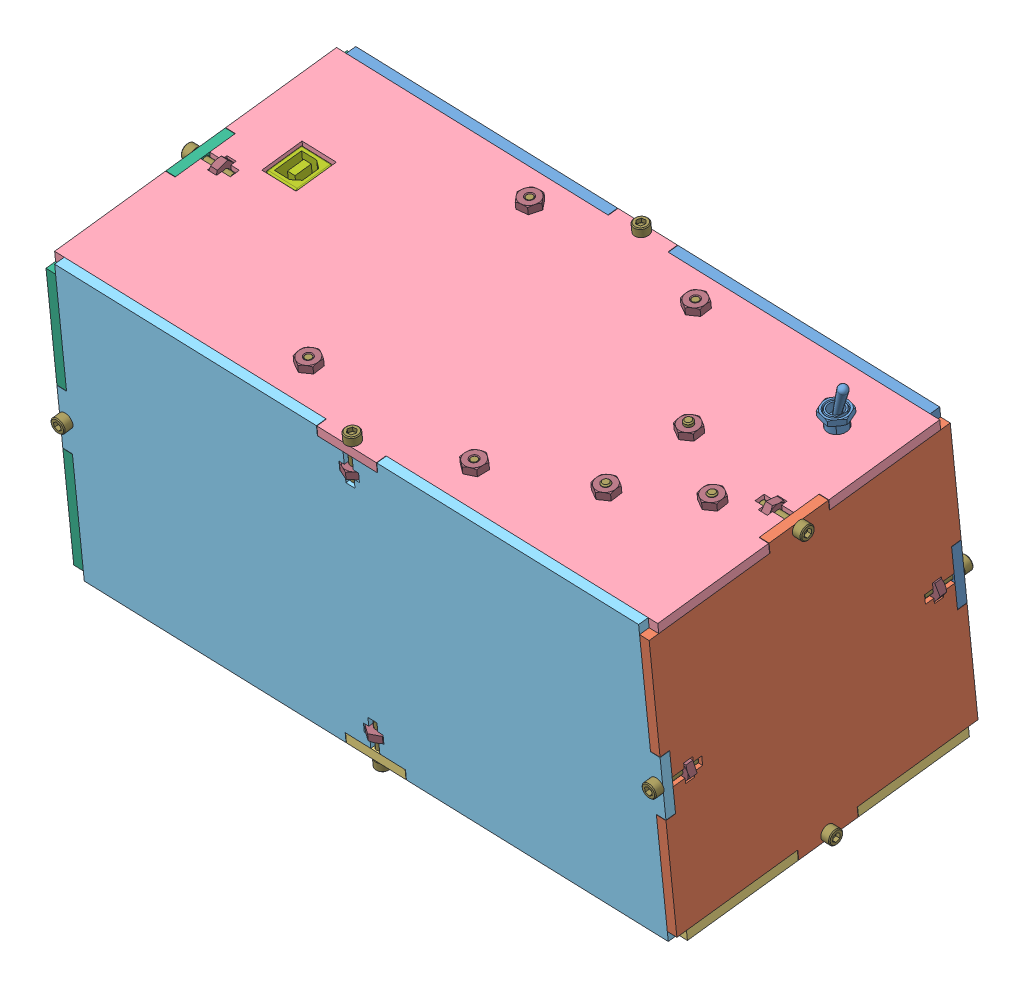
SolidWorks assembly BoxAssembly, configuration Default. Lengths in mm.
Overall size (208.93 126.48 114.42).
72 component instances, 20 part files, 161 mates.
Components (placement in the parent):
- FrontWall-3: FrontWall [Default] at (-132.6402 325.3344 298.0209) x (0.999441 -0.033422 0.001061) z (-0.005434 -0.131017 0.991365) size (200 100 3.18)
- TopWall-2: TopWall [Default] at (-32.9678 315.4413 347.6953) x (0.032994 0.990817 0.131126) z (-0.999441 0.033422 -0.001061) size (100 100 3.18)
- RightWall-1: RightWall [Default] at (-134.5616 269.2427 341.0329) x (0.005434 0.131017 -0.991365) z (0.032994 0.990817 0.131126) size (100 200 3.18)
- LeftWall-5: LeftWall [Default] at (-131.3671 365.1735 353.7285) x (-0.005434 -0.131017 0.991365) z (0.032994 0.990817 0.131126) size (100 200 3.18)
- BackWall-1: BackWall [Default] at (-133.1663 312.6493 394.0049) x (0.999441 -0.033422 0.001061) z (-0.005434 -0.131017 0.991365) size (200 100 3.18)
- BottomWall-1: BottomWall [Default] at (-232.856 322.1257 347.4831) x (-0.032994 -0.990817 -0.131126) z (0.999441 -0.033422 0.001061) size (100 100 3.18)
- ArduinoUno (2)-1: ArduinoUno (2) [Default] at (-216.6407 331.9316 348.8679) x (-0.032994 -0.990817 -0.131126) z (-0.005434 -0.131017 0.991365) size (74.8 12.1 53.3)
- 25x.5 Aluminum Hex Female Female Standoff-1: 25x.5 Aluminum Hex Female Female Standoff [Default] at (-222.2818 352.5481 327.2013) x (0.00659 0.165736 -0.986148) z (0.999441 -0.033422 0.001061) size (6.35 8.06 12.7)
- 25x.5 Aluminum Hex Female Female Standoff-2: 25x.5 Aluminum Hex Female Female Standoff [Default] at (-222.4914 347.8052 375.294) x (-0.020236 -0.579254 0.814896) z (0.999441 -0.033422 0.001061) size (6.35 8.06 12.7)
- 25x.5 Aluminum Hex Female Female Standoff-3: 25x.5 Aluminum Hex Female Female Standoff [Default] at (-224.041 300.21 335.708) x (0.001061 -0.000018 -0.999999) z (0.999441 -0.033422 0.001061) size (6.35 8.06 12.7)
- 25x.5 Aluminum Hex Female Female Standoff-4: 25x.5 Aluminum Hex Female Female Standoff [Default] at (-224.1926 296.5547 363.367) x (-0.023209 -0.670488 0.741557) z (-0.999441 0.033422 -0.001061) size (6.35 8.06 12.7)
- breadboardbracket-1: breadboardbracket [Default] at (-130.399 365.2511 352.8986) x (-0.999441 0.033422 -0.001061) z (-0.032994 -0.990817 -0.131126) size (93 81 12)
- ledmatrix-1: ledmatrix [Default] at (-75.3439 276.7943 322.4548) x (-0.999441 0.033422 -0.001061) z (-0.032994 -0.990817 -0.131126) size (26 20 7)
- ledmatrix-2: ledmatrix [Default] at (-75.5838 271.5752 361.9513) x (-0.999441 0.033422 -0.001061) z (-0.032994 -0.990817 -0.131126) size (26 20 7)
- Ultrasonic holder-1: Ultrasonic holder [Default] at (-120.0997 285.6163 366.5083) x (0.141058 -0.981567 -0.128949) z (0.989986 0.139139 0.023815) size (23.16 47 32.54)
- socket head cap screw_ai-1: socket head cap screw_ai [HX-SHCS 0.112-40x0.5x0.5-N] at (-237.2829 274.6616 341.186) x (0.999441 -0.033422 0.001061) z (0.013936 0.445184 0.895331) size (15.54 4.65 4.65)
- socket head cap screw_ai-2: socket head cap screw_ai [HX-SHCS 0.112-40x0.5x0.5-N] at (-230.5699 328.9824 295.0967) x (-0.005434 -0.131017 0.991365) z (-0.991365 0.130596 0.011825) size (15.54 4.65 4.65)
- socket head cap screw_ai-3: socket head cap screw_ai [HX-SHCS 0.112-40x0.5x0.5-N] at (-134.3946 272.7128 293.0744) x (0.032994 0.990817 0.131126) z (0.177502 -0.134921 0.974828) size (15.54 4.65 4.65)
- socket head cap screw_ai-4: socket head cap screw_ai [HX-SHCS 0.112-40x0.5x0.5-N] at (-134.9163 260.1352 388.2454) x (0.032994 0.990817 0.131126) z (0.089842 0.127726 -0.987732) size (15.54 4.65 4.65)
- socket head cap screw_ai-5: socket head cap screw_ai [HX-SHCS 0.112-40x0.5x0.5-N] at (-31.7083 267.7871 341.4043) x (-0.999441 0.033422 -0.001061) z (0.001061 0.063432 0.997986) size (15.54 4.65 4.65)
- socket head cap screw_ai-6: socket head cap screw_ai [HX-SHCS 0.112-40x0.5x0.5-N] at (-35.2539 308.5846 400.0817) x (0.005434 0.131017 -0.991365) z (0.9972 0.073227 0.015144) size (15.54 4.65 4.65)
- socket head cap screw_ai-7: socket head cap screw_ai [HX-SHCS 0.112-40x0.5x0.5-N] at (-231.1443 315.1352 399.8737) x (0.005434 0.131017 -0.991365) z (0.991365 0.129184 0.022507) size (15.54 4.65 4.65)
- socket head cap screw_ai-8: socket head cap screw_ai [HX-SHCS 0.112-40x0.5x0.5-N] at (-234.1155 369.7799 353.7741) x (0.999441 -0.033422 0.001061) z (-0.001061 0.000018 0.999999) size (15.54 4.65 4.65)
- socket head cap screw_ai-9: socket head cap screw_ai [HX-SHCS 0.112-40x0.5x0.5-N] at (-28.5409 362.9054 353.9924) x (-0.999441 0.033422 -0.001061) z (0.001061 0.063432 0.997986) size (15.54 4.65 4.65)
- socket head cap screw_ai-10: socket head cap screw_ai [HX-SHCS 0.112-40x0.5x0.5-N] at (-34.6795 322.4318 295.3047) x (-0.005434 -0.131017 0.991365) z (-0.991365 0.130596 0.011825) size (15.54 4.65 4.65)
- socket head cap screw_ai-11: socket head cap screw_ai [HX-SHCS 0.112-40x0.5x0.5-N] at (-130.9075 377.4318 306.933) x (-0.032994 -0.990817 -0.131126) z (0.175575 -0.134903 0.975179) size (15.54 4.65 4.65)
- socket head cap screw_ai-12: socket head cap screw_ai [HX-SHCS 0.112-40x0.5x0.5-N] at (-131.4292 364.8542 402.104) x (-0.032994 -0.990817 -0.131126) z (0.131126 -0.134355 0.982219) size (15.54 4.65 4.65)
- machine screw nut hex_ai-1: machine screw nut hex_ai [MSHXNUT 0.112-40-S-N] at (-227.0085 274.318 341.1969) x (0.027312 0.834212 0.550767) z (-0.999441 0.033422 -0.001061) size (6.35 7.33 2.49)
- machine screw nut hex_ai-2: machine screw nut hex_ai [MSHXNUT 0.112-40-S-N] at (-230.6244 327.669 305.0349) x (0.849044 -0.524352 -0.064644) z (0.005434 0.131017 -0.991365) size (6.35 7.33 2.49)
- socket button head cap screw_ai-1: socket button head cap screw_ai [SBHCSCREW 0.112-40x0.375-HX-N] at (-235.2151 296.9232 363.3553) x (0.999441 -0.033422 0.001061) z (-0.001061 0.000018 0.999999) size (11.02 5.41 5.41)
- socket button head cap screw_ai-2: socket button head cap screw_ai [SBHCSCREW 0.112-40x0.375-HX-N] at (-233.3042 352.9167 327.1896) x (0.999441 -0.033422 0.001061) z (0.012253 0.336514 -0.941599) size (11.02 5.41 5.41)
- socket button head cap screw_ai-3: socket button head cap screw_ai [SBHCSCREW 0.112-40x0.375-HX-N] at (-235.0634 300.5786 335.6962) x (0.999441 -0.033422 0.001061) z (-0.001061 0.000018 0.999999) size (11.02 5.41 5.41)
- socket button head cap screw_ai-4: socket button head cap screw_ai [SBHCSCREW 0.112-40x0.375-HX-N] at (-233.5139 348.1738 375.2823) x (0.999441 -0.033422 0.001061) z (-0.001061 0.000018 0.999999) size (11.02 5.41 5.41)
- machine screw nut hex_ai-3: machine screw nut hex_ai [MSHXNUT 0.112-40-S-N] at (-224.0963 369.4449 353.7847) x (0.025816 0.751053 -0.659737) z (-0.999441 0.033422 -0.001061) size (6.35 7.33 2.49)
- machine screw nut hex_ai-5: machine screw nut hex_ai [MSHXNUT 0.112-40-S-N] at (-131.2383 367.4991 305.6185) x (0.9951 -0.044802 0.088146) z (0.032994 0.990817 0.131126) size (6.35 7.33 2.49)
- machine screw nut hex_ai-10: machine screw nut hex_ai [MSHXNUT 0.112-40-S-N] at (-35.1994 309.898 390.1435) x (0.24437 0.961148 0.128364) z (-0.005434 -0.131017 0.991365) size (6.35 7.33 2.49)
- machine screw nut hex_ai-13: machine screw nut hex_ai [MSHXNUT 0.112-40-S-N] at (-41.7275 268.1221 341.3937) x (-0.031999 -0.965156 -0.259711) z (0.999441 -0.033422 0.001061) size (6.35 7.33 2.49)
- machine screw nut hex_ai-15: machine screw nut hex_ai [MSHXNUT 0.112-40-S-N] at (-134.5855 270.0679 389.5599) x (0.996358 -0.042929 0.073673) z (-0.032994 -0.990817 -0.131126) size (6.35 7.33 2.49)
- machine screw nut hex_ai-16: machine screw nut hex_ai [MSHXNUT 0.112-40-S-N] at (-134.0639 282.6456 294.3889) x (0.993355 -0.046983 0.105067) z (-0.032994 -0.990817 -0.131126) size (6.35 7.33 2.49)
- machine screw nut hex_ai-17: machine screw nut hex_ai [MSHXNUT 0.112-40-S-N] at (-231.0898 316.4487 389.9354) x (-0.995136 -0.096803 -0.018248) z (-0.005434 -0.131017 0.991365) size (6.35 7.33 2.49)
- machine screw nut hex_ai-18: machine screw nut hex_ai [MSHXNUT 0.112-40-S-N] at (-34.734 321.1183 305.243) x (-0.780752 0.619996 0.077658) z (0.005434 0.131017 -0.991365) size (6.35 7.33 2.49)
- machine screw nut hex_ai-19: machine screw nut hex_ai [MSHXNUT 0.112-40-S-N] at (-38.5601 363.2405 353.9817) x (0.015292 0.428602 -0.903364) z (0.999441 -0.033422 0.001061) size (6.35 7.33 2.49)
- machine screw nut hex_ai-20: machine screw nut hex_ai [MSHXNUT 0.112-40-S-N] at (-131.7599 354.9214 400.7895) x (0.991137 -0.015544 -0.131934) z (0.032994 0.990817 0.131126) size (6.35 7.33 2.49)
- Part1^BoxAssembly-1: Part1^BoxAssembly [Default] at origin (virtual)
- ledmatrix_mount-4: ledmatrix_mount [Default] at (-64.0966 276.3101 315.6566) x (-0.999441 0.033422 -0.001061) z (-0.032994 -0.990817 -0.131126) size (2.5 4 3.18)
- socket head cap screw_ai-25: socket head cap screw_ai [HX-SHCS 0.073-72x0.375x0.375-N] at (-64.3757 268.5304 314.614) x (0.032994 0.990817 0.131126) z (-0.131126 -0.125772 0.983355) size (11.38 3 3)
- socket head cap screw_ai-31: socket head cap screw_ai [HX-SHCS 0.112-40x0.375x0.375-N] at (-158.3091 354.5743 388.3973) x (0.032994 0.990817 0.131126) z (-0.131126 -0.125772 0.983355) size (12.37 4.65 4.65)
- socket head cap screw_ai-32: socket head cap screw_ai [HX-SHCS 0.112-40x0.375x0.375-N] at (-157.9098 364.2022 315.5464) x (0.032994 0.990817 0.131126) z (-0.131126 -0.125772 0.983355) size (12.37 4.65 4.65)
- socket head cap screw_ai-33: socket head cap screw_ai [HX-SHCS 0.112-40x0.375x0.375-N] at (-103.3398 352.7362 388.4556) x (0.032994 0.990817 0.131126) z (-0.131126 -0.125772 0.983355) size (12.37 4.65 4.65)
- socket head cap screw_ai-34: socket head cap screw_ai [HX-SHCS 0.112-40x0.375x0.375-N] at (-102.9405 362.364 315.6048) x (0.032994 0.990817 0.131126) z (-0.131126 -0.125772 0.983355) size (12.37 4.65 4.65)
- machine screw nut hex_ai-28: machine screw nut hex_ai [MSHXNUT 0.112-40-S-N] at (-102.5276 374.7631 317.2457) x (0.999038 -0.028901 -0.032994) z (0.032994 0.990817 0.131126) size (6.35 7.33 2.49)
- machine screw nut hex_ai-29: machine screw nut hex_ai [MSHXNUT 0.112-40-S-N] at (-157.4969 376.6013 317.1873) x (-0.920743 0.081167 -0.381634) z (0.032994 0.990817 0.131126) size (6.35 7.33 2.49)
- machine screw nut hex_ai-30: machine screw nut hex_ai [MSHXNUT 0.112-40-S-N] at (-157.8962 366.9734 390.0382) x (0.999038 -0.028901 -0.032994) z (0.032994 0.990817 0.131126) size (6.35 7.33 2.49)
- machine screw nut hex_ai-31: machine screw nut hex_ai [MSHXNUT 0.112-40-S-N] at (-102.9269 365.1352 390.0965) x (-0.405905 0.133174 -0.90416) z (0.032994 0.990817 0.131126) size (6.35 7.33 2.49)
- socket head cap screw_ai-38: socket head cap screw_ai [HX-SHCS 0.112-40x0.375x0.375-N] at (-117.1036 266.4185 336.2849) x (0.032994 0.990817 0.131126) z (-0.131126 -0.125772 0.983355) size (12.37 4.65 4.65)
- socket head cap screw_ai-39: socket head cap screw_ai [HX-SHCS 0.112-40x0.375x0.375-N] at (-117.1467 265.3799 344.1434) x (0.032994 0.990817 0.131126) z (-0.983659 0.055426 -0.171299) size (12.37 4.65 4.65)
- machine screw nut hex_ai-36: machine screw nut hex_ai [MSHXNUT 0.112-40-S-N] at (-116.7237 277.8268 337.7946) x (-0.342493 -0.112045 0.932815) z (0.032994 0.990817 0.131126) size (6.35 7.33 2.49)
- machine screw nut hex_ai-37: machine screw nut hex_ai [MSHXNUT 0.112-40-S-N] at (-116.7668 276.7882 345.6532) x (0.999038 -0.028901 -0.032994) z (0.032994 0.990817 0.131126) size (6.35 7.33 2.49)
- socket head cap screw_ai-40: socket head cap screw_ai [HX-SHCS 0.112-40x0.375x0.375-N] at (-211.493 352.1873 327.2127) x (-0.999441 0.033422 -0.001061) z (0.001061 0.063432 0.997986) size (12.37 4.65 4.65)
- socket head cap screw_ai-42: socket head cap screw_ai [HX-SHCS 0.112-40x0.375x0.375-N] at (-213.2523 299.8493 335.7194) x (-0.999441 0.033422 -0.001061) z (0.001061 0.063432 0.997986) size (12.37 4.65 4.65)
- socket head cap screw_ai-43: socket head cap screw_ai [HX-SHCS 0.112-40x0.375x0.375-N] at (-213.4039 296.1939 363.3785) x (-0.999441 0.033422 -0.001061) z (0.001061 0.063432 0.997986) size (12.37 4.65 4.65)
- socket head cap screw_ai-44: socket head cap screw_ai [HX-SHCS 0.112-40x0.375x0.375-N] at (-211.7027 347.4445 375.3055) x (-0.999441 0.033422 -0.001061) z (0.001061 0.063432 0.997986) size (12.37 4.65 4.65)
- 9V Battery Holder-1: 9V Battery Holder [Default] at (-62.6627 360.8198 361.7121) x (0.005434 0.131017 -0.991365) z (-0.032994 -0.990817 -0.131126) size (53.5 30 19.31)
- socket head cap screw_ai-45: socket head cap screw_ai [HX-SHCS 0.112-40x0.375x0.375-N] at (-73.4286 358.5748 347.4866) x (0.032994 0.990817 0.131126) z (-0.131126 -0.125772 0.983355) size (12.37 4.65 4.65)
- socket head cap screw_ai-46: socket head cap screw_ai [HX-SHCS 0.112-40x0.375x0.375-N] at (-52.0388 355.35 361.0475) x (0.032994 0.990817 0.131126) z (-0.131126 -0.125772 0.983355) size (12.37 4.65 4.65)
- socket head cap screw_ai-47: socket head cap screw_ai [HX-SHCS 0.112-40x0.375x0.375-N] at (-73.6015 354.2671 374.6559) x (0.032994 0.990817 0.131126) z (-0.131126 -0.125772 0.983355) size (12.37 4.65 4.65)
- machine screw nut hex_ai-38: machine screw nut hex_ai [MSHXNUT 0.112-40-S-N] at (-51.6487 367.0668 362.5981) x (0.999038 -0.028901 -0.032994) z (0.032994 0.990817 0.131126) size (6.35 7.33 2.49)
- machine screw nut hex_ai-39: machine screw nut hex_ai [MSHXNUT 0.112-40-S-N] at (-73.2114 365.9839 376.2065) x (0.999038 -0.028901 -0.032994) z (0.032994 0.990817 0.131126) size (6.35 7.33 2.49)
- machine screw nut hex_ai-40: machine screw nut hex_ai [MSHXNUT 0.112-40-S-N] at (-73.0619 369.5869 348.944) x (0.999038 -0.028901 -0.032994) z (0.032994 0.990817 0.131126) size (6.35 7.33 2.49)
- Half Breadboard-Simple-1: Half Breadboard-Simple [Default] at (-131.1665 357.2189 351.6311) x (0.005434 0.131017 -0.991365) z (0.999441 -0.033422 0.001061) size (55.6 8.15 85)
- HC-SR04 WITH CONFIGURATIONS-2: HC-SR04 WITH CONFIGURATIONS [With Oscillator] at (-106.7826 281.9081 342.8203) x (0.005434 0.131017 -0.991365) z (-0.032994 -0.990817 -0.131126) size (45.2 26.75 18.52)
- Panel Mount SPDT-1: Panel Mount SPDT [Default] at (-48.459 357.4874 323.1476) x (0.196219 0.122222 -0.972913) z (0.980005 -0.05783 0.190385) size (8 31.74 12.7)
Mates (geometry in assembly coordinates):
- Coincident15: coincident aligned: plane of FrontWall-3 through (-132.6402 325.3344 298.0209) normal (0.032994 0.990817 0.131126); plane of TopWall-2 through (-32.9678 315.4413 347.6953) normal (0.032994 0.990817 0.131126)
- Perpendicular1: perpendicular: plane of FrontWall-3 through (-132.6402 325.3344 298.0209) normal (0.005434 0.131017 -0.991365); plane of TopWall-2 through (-32.9678 315.4413 347.6953) normal (0.999441 -0.033422 0.001061)
- Coincident17: coincident aligned: line of FrontWall-3 through (-33.0392 311.7912 299.9847) axis (0.032994 0.990817 0.131126); line of TopWall-2 through (-33.0433 311.6674 299.9684) axis (0.032994 0.990817 0.131126)
- Parallel3: parallel anti-aligned: plane of RightWall-1 through (-34.2409 275.6022 291.9878) normal (0.999441 -0.033422 0.001061); plane of TopWall-2 through (-36.146 315.5476 347.692) normal (-0.999441 0.033422 -0.001061)
- Coincident21: coincident anti-aligned: plane of FrontWall-3 through (-132.6402 325.3344 298.0209) normal (0.999441 -0.033422 0.001061); plane of RightWall-1 through (-134.5616 269.2427 341.0329) normal (-0.999441 0.033422 -0.001061)
- Coincident22: coincident anti-aligned: line of FrontWall-3 through (-132.6858 278.8942 291.8832) axis (0.999441 -0.033422 0.001061); line of RightWall-1 through (-124.3155 278.6143 291.8921) axis (-0.999441 0.033422 -0.001061)
- Parallel4: parallel anti-aligned: plane of TopWall-2 through (-36.146 315.5476 347.692) normal (-0.999441 0.033422 -0.001061); plane of LeftWall-5 through (-31.0464 371.533 304.6834) normal (0.999441 -0.033422 0.001061)
- Coincident25: coincident anti-aligned: line of TopWall-2 through (-37.7421 267.3006 331.3459) axis (-0.005434 -0.131017 0.991365); line of RightWall-1 through (-37.7876 266.2033 339.6486) axis (0.005434 0.131017 -0.991365)
- Parallel7: parallel anti-aligned: plane of TopWall-2 through (-32.9678 315.4413 347.6953) normal (0.005434 0.131017 -0.991365); plane of LeftWall-5 through (-131.3671 365.1735 353.7285) normal (-0.005434 -0.131017 0.991365)
- Parallel8: parallel aligned: plane of FrontWall-3 through (-132.6402 325.3344 298.0209) normal (0.999441 -0.033422 0.001061); plane of LeftWall-5 through (-131.3671 365.1735 353.7285) normal (0.999441 -0.033422 0.001061)
- Coincident30: coincident anti-aligned: line of FrontWall-3 through (-129.5963 371.6743 304.1618) axis (0.999441 -0.033422 0.001061); line of LeftWall-5 through (-121.2259 371.3944 304.1707) axis (-0.999441 0.033422 -0.001061)
- Coincident31: coincident anti-aligned: line of TopWall-2 through (-34.55 363.7946 364.038) axis (0.005434 0.131017 -0.991365); line of LeftWall-5 through (-34.442 366.3986 344.3346) axis (-0.005434 -0.131017 0.991365)
- Coincident32: coincident aligned: plane of FrontWall-3 through (-132.6402 325.3344 298.0209) normal (0.999441 -0.033422 0.001061); plane of BackWall-1 through (-133.1663 312.6493 394.0049) normal (0.999441 -0.033422 0.001061)
- Coincident33: coincident aligned: plane of TopWall-2 through (-32.9678 315.4413 347.6953) normal (0.032994 0.990817 0.131126); plane of BackWall-1 through (-133.1663 312.6493 394.0049) normal (0.032994 0.990817 0.131126)
- Coincident34: coincident aligned: line of TopWall-2 through (-33.1728 310.7933 394.3077) axis (0.032994 0.990817 0.131126); line of BackWall-1 through (-33.5481 299.5228 392.8162) axis (0.032994 0.990817 0.131126)
- Coincident36: coincident anti-aligned: plane of FrontWall-3 through (-132.6402 325.3344 298.0209) normal (0.032994 0.990817 0.131126); plane of BottomWall-1 through (-232.856 322.1257 347.4831) normal (-0.032994 -0.990817 -0.131126)
- Coincident37: coincident anti-aligned: plane of LeftWall-5 through (-131.3671 365.1735 353.7285) normal (-0.005434 -0.131017 0.991365); plane of BottomWall-1 through (-232.856 322.1257 347.4831) normal (0.005434 0.131017 -0.991365)
- Coincident38: coincident aligned: line of BackWall-1 through (-232.7846 325.7758 395.1936) axis (-0.032994 -0.990817 -0.131126); line of BottomWall-1 through (-233.1599 314.5052 393.7021) axis (-0.032994 -0.990817 -0.131126)
- Concentric2: concentric anti-aligned: circle of ArduinoUno (2)-1; circle of 25x.5 Aluminum Hex Female Female Standoff-2
- Concentric3: concentric anti-aligned: circle of ArduinoUno (2)-1; circle of 25x.5 Aluminum Hex Female Female Standoff-1
- Concentric4: concentric anti-aligned: circle of ArduinoUno (2)-1; circle of 25x.5 Aluminum Hex Female Female Standoff-3
- Concentric5: concentric anti-aligned: cylinder of ArduinoUno (2)-1 through (-216.2471 296.2889 363.3755) axis (-0.999441 0.033422 -0.001061) radius 1.6; circle of 25x.5 Aluminum Hex Female Female Standoff-4
- Concentric6: concentric anti-aligned: cone of BottomWall-1; cone of 25x.5 Aluminum Hex Female Female Standoff-3 through (-229.7528 300.401 335.7019) axis (0.999441 -0.033422 0.001061)
- Coincident51: coincident aligned: circle of ArduinoUno (2)-1; plane of 25x.5 Aluminum Hex Female Female Standoff-3 through (-217.6946 299.9978 335.7147) normal (0.999441 -0.033422 0.001061)
- Parallel12: parallel aligned: plane of BottomWall-1 through (-232.856 322.1257 347.4831) normal (-0.999441 0.033422 -0.001061); plane of ArduinoUno (2)-1 through (-217.5846 302.7262 318.1208) normal (-0.999441 0.033422 -0.001061)
- Parallel16: parallel anti-aligned: line of TopWall-2 through (-34.873 355.3868 403.3995) axis (0.005434 0.131017 -0.991365); line of breadboardbracket-1 through (-84.1943 355.6395 352.8903) axis (-0.005434 -0.131017 0.991365)
- Parallel21: parallel anti-aligned: line of LeftWall-5 through (-231.2606 370.3563 363.953) axis (-0.005434 -0.131017 0.991365); line of breadboardbracket-1 through (-177.0333 362.9402 382.0945) axis (0.005434 0.131017 -0.991365)
- Distance6: distance = 24 mm: line of BackWall-1 through (-124.8216 262.7742 387.4592) axis (0.999441 -0.033422 0.001061); line of Ultrasonic holder-1 through (-107.255 268.4621 364.3116) axis (-0.999441 0.033422 -0.001061)
- Distance7: distance = 102 mm: line of Ultrasonic holder-1 through (-129.0967 279.4572 318.2356) axis (-0.005434 -0.131017 0.991365); line of BottomWall-1 through (-231.1689 276.9232 331.5574) axis (0.005434 0.131017 -0.991365)
- Coincident88: coincident anti-aligned: plane of LeftWall-5 through (-131.3671 365.1735 353.7285) normal (-0.032994 -0.990817 -0.131126); plane of breadboardbracket-1 through (-130.399 365.2511 352.8986) normal (0.032994 0.990817 0.131126)
- Distance8: distance = 8.2 mm: line of breadboardbracket-1 through (-156.2368 356.8339 392.4973) axis (-0.999441 0.033422 -0.001061); line of LeftWall-5 through (-231.5656 362.3815 400.0381) axis (0.999441 -0.033422 0.001061)
- Distance9: distance = 50 mm: line of breadboardbracket-1 through (-84.1943 355.6395 352.8903) axis (-0.005434 -0.131017 0.991365); line of TopWall-2 through (-34.873 355.3868 403.3995) axis (0.005434 0.131017 -0.991365)
- Concentric7: concentric anti-aligned: cylinder of BottomWall-1 through (-234.4397 274.5665 341.189) axis (0.999441 -0.033422 0.001061) radius 1.55; cylinder of socket head cap screw_ai-1 through (-269.0152 275.7227 341.1523) axis (-0.999441 0.033422 -0.001061) radius 2.3241
- Coincident89: coincident anti-aligned: plane of BottomWall-1 through (-232.856 322.1257 347.4831) normal (-0.999441 0.033422 -0.001061); plane of socket head cap screw_ai-1 through (-234.3691 276.6461 340.1539) normal (0.999441 -0.033422 0.001061)
- Concentric8: concentric anti-aligned: cylinder of FrontWall-3 through (-230.5854 328.6097 297.9169) axis (-0.005434 -0.131017 0.991365) radius 1.55; cylinder of socket head cap screw_ai-2 through (-230.3974 333.1422 263.6208) axis (0.005434 0.131017 -0.991365) radius 2.3241
- Coincident90: coincident anti-aligned: plane of FrontWall-3 through (-132.6402 325.3344 298.0209) normal (0.005434 0.131017 -0.991365); plane of socket head cap screw_ai-2 through (-230.2809 330.8937 298.2204) normal (-0.005434 -0.131017 0.991365)
- Concentric9: concentric anti-aligned: cylinder of RightWall-1 through (-134.3008 275.5315 293.4474) axis (0.032994 0.990817 0.131126) radius 1.55; cylinder of socket head cap screw_ai-3 through (-135.4422 241.2544 288.9111) axis (-0.032994 -0.990817 -0.131126) radius 2.3241
- Coincident91: coincident anti-aligned: plane of RightWall-1 through (-134.5616 269.2427 341.0329) normal (-0.032994 -0.990817 -0.131126); plane of socket head cap screw_ai-3 through (-136.5867 275.5522 293.8665) normal (0.032994 0.990817 0.131126)
- Concentric10: concentric anti-aligned: cylinder of RightWall-1 through (-134.8224 262.9538 388.6184) axis (0.032994 0.990817 0.131126) radius 1.55; cylinder of socket head cap screw_ai-4 through (-135.9639 228.6767 384.0822) axis (-0.032994 -0.990817 -0.131126) radius 2.3241
- Coincident92: coincident anti-aligned: plane of RightWall-1 through (-134.5616 269.2427 341.0329) normal (-0.032994 -0.990817 -0.131126); plane of socket head cap screw_ai-4 through (-132.509 262.8507 388.8155) normal (0.032994 0.990817 0.131126)
- Concentric11: concentric anti-aligned: cylinder of TopWall-2 through (-34.5515 267.8821 341.4013) axis (-0.999441 0.033422 -0.001061) radius 1.55; cylinder of socket head cap screw_ai-5 through (0.0239 266.7259 341.438) axis (0.999441 -0.033422 0.001061) radius 2.3241
- Coincident93: coincident anti-aligned: plane of TopWall-2 through (-32.9678 315.4413 347.6953) normal (0.999441 -0.033422 0.001061); plane of socket head cap screw_ai-5 through (-34.6292 265.564 341.5487) normal (-0.999441 0.033422 -0.001061)
- Concentric12: concentric aligned: cylinder of BackWall-1 through (-35.2211 309.3739 394.1089) axis (-0.005434 -0.131017 0.991365) radius 1.55; cylinder of socket head cap screw_ai-6 through (-35.4264 304.4248 431.5575) axis (-0.005434 -0.131017 0.991365) radius 2.3241
- Coincident94: coincident anti-aligned: plane of BackWall-1 through (-133.1836 312.2326 397.1575) normal (-0.005434 -0.131017 0.991365); plane of socket head cap screw_ai-6 through (-35.4117 311.2551 397.5642) normal (0.005434 0.131017 -0.991365)
- Concentric13: concentric aligned: cylinder of BackWall-1 through (-231.1115 315.9246 393.9009) axis (-0.005434 -0.131017 0.991365) radius 1.55; cylinder of socket head cap screw_ai-7 through (-231.3168 310.9754 431.3495) axis (-0.005434 -0.131017 0.991365) radius 2.3241
- Coincident95: coincident anti-aligned: plane of BackWall-1 through (-133.1836 312.2326 397.1575) normal (-0.005434 -0.131017 0.991365); plane of socket head cap screw_ai-7 through (-231.4333 317.7924 397.3537) normal (0.005434 0.131017 -0.991365)
- Concentric14: concentric anti-aligned: cylinder of BottomWall-1 through (-231.2723 369.6849 353.7771) axis (0.999441 -0.033422 0.001061) radius 1.55; cylinder of socket head cap screw_ai-8 through (-265.8477 370.8411 353.7404) axis (-0.999441 0.033422 -0.001061) radius 2.3241
- Coincident96: coincident anti-aligned: plane of BottomWall-1 through (-232.856 322.1257 347.4831) normal (-0.999441 0.033422 -0.001061); plane of socket head cap screw_ai-8 through (-231.1946 372.0077 353.7771) normal (0.999441 -0.033422 0.001061)
- Concentric15: concentric anti-aligned: cylinder of TopWall-2 through (-31.3841 363.0005 353.9894) axis (-0.999441 0.033422 -0.001061) radius 1.55; cylinder of socket head cap screw_ai-9 through (3.1913 361.8443 354.0261) axis (0.999441 -0.033422 0.001061) radius 2.3241
- Coincident97: coincident anti-aligned: plane of TopWall-2 through (-32.9678 315.4413 347.6953) normal (0.999441 -0.033422 0.001061); plane of socket head cap screw_ai-9 through (-31.4618 360.6824 354.1368) normal (-0.999441 0.033422 -0.001061)
- Concentric16: concentric anti-aligned: cylinder of FrontWall-3 through (-34.695 322.059 298.125) axis (-0.005434 -0.131017 0.991365) radius 1.55; cylinder of socket head cap screw_ai-10 through (-34.507 326.5916 263.8289) axis (0.005434 0.131017 -0.991365) radius 2.3241
- Coincident98: coincident anti-aligned: plane of FrontWall-3 through (-132.6402 325.3344 298.0209) normal (0.005434 0.131017 -0.991365); plane of socket head cap screw_ai-10 through (-34.3905 324.343 298.4285) normal (-0.005434 -0.131017 0.991365)
- Concentric17: concentric aligned: cylinder of LeftWall-5 through (-131.1063 371.4624 306.143) axis (0.032994 0.990817 0.131126) radius 1.55; cylinder of socket head cap screw_ai-11 through (-129.8599 408.8903 311.0962) axis (0.032994 0.990817 0.131126) radius 2.3241
- Coincident99: coincident anti-aligned: plane of LeftWall-5 through (-131.2622 368.3243 354.1455) normal (0.032994 0.990817 0.131126); plane of socket head cap screw_ai-11 through (-128.7147 374.5919 306.1453) normal (-0.032994 -0.990817 -0.131126)
- Concentric18: concentric aligned: cylinder of LeftWall-5 through (-131.628 358.8847 401.314) axis (0.032994 0.990817 0.131126) radius 1.55; cylinder of socket head cap screw_ai-12 through (-130.3816 396.3126 406.2673) axis (0.032994 0.990817 0.131126) radius 2.3241
- Coincident100: coincident anti-aligned: plane of LeftWall-5 through (-131.2622 368.3243 354.1455) normal (0.032994 0.990817 0.131126); plane of socket head cap screw_ai-12 through (-129.2203 362.0001 401.4188) normal (-0.032994 -0.990817 -0.131126)
- Concentric19: concentric aligned: cylinder of socket head cap screw_ai-1 through (-269.0152 275.7227 341.1523) axis (-0.999441 0.033422 -0.001061) radius 1.4224; cylinder of machine screw nut hex_ai-1 through (-201.985 273.4812 341.2235) axis (-0.999441 0.033422 -0.001061) radius 1.4224
- Concentric20: concentric aligned: cylinder of socket head cap screw_ai-2 through (-230.3974 333.1422 263.6208) axis (0.005434 0.131017 -0.991365) radius 1.4224; cylinder of machine screw nut hex_ai-2 through (-230.7605 324.3886 329.8562) axis (0.005434 0.131017 -0.991365) radius 1.4224
- Coincident101: coincident anti-aligned: plane of BottomWall-1 through (-232.5161 330.956 305.459) normal (-0.005434 -0.131017 0.991365); plane of machine screw nut hex_ai-2 through (-232.5612 324.5844 304.6167) normal (0.005434 0.131017 -0.991365)
- Parallel22: parallel anti-aligned: plane of BottomWall-1 through (-232.5161 330.956 305.459) normal (-0.032994 -0.990817 -0.131126); plane of machine screw nut hex_ai-2 through (-232.3652 330.55 307.917) normal (0.032994 0.990817 0.131126)
- Width1: width anti-aligned: plane of machine screw nut hex_ai-1 through (-226.9377 276.3359 338.1369) normal (-0.999441 0.033422 -0.001061); plane of RightWall-1 through (-224.4499 276.2528 338.1396) normal (0.999441 -0.033422 0.001061); plane of machine screw nut hex_ai-1 through (-227.3216 272.5414 339.4473) normal (0.999441 -0.033422 0.001061); plane of RightWall-1 through (-224.3232 272.4411 339.4505) normal (-0.999441 0.033422 -0.001061)
- Coincident103: coincident anti-aligned: plane of ArduinoUno (2)-1 through (-217.5846 302.7262 318.1208) normal (-0.999441 0.033422 -0.001061); plane of 25x.5 Aluminum Hex Female Female Standoff-4 through (-217.8462 296.3424 363.3738) normal (0.999441 -0.033422 0.001061)
- Coincident104: coincident anti-aligned: plane of ArduinoUno (2)-1 through (-217.5846 302.7262 318.1208) normal (-0.999441 0.033422 -0.001061); plane of 25x.5 Aluminum Hex Female Female Standoff-2 through (-216.145 347.593 375.3007) normal (0.999441 -0.033422 0.001061)
- Coincident105: coincident anti-aligned: plane of ArduinoUno (2)-1 through (-217.5846 302.7262 318.1208) normal (-0.999441 0.033422 -0.001061); plane of 25x.5 Aluminum Hex Female Female Standoff-1 through (-215.9353 352.3359 327.208) normal (0.999441 -0.033422 0.001061)
- Coincident106: coincident anti-aligned: plane of BottomWall-1 through (-229.6778 322.0194 347.4864) normal (0.999441 -0.033422 0.001061); plane of 25x.5 Aluminum Hex Female Female Standoff-4 through (-230.5391 296.7669 363.3603) normal (-0.999441 0.033422 -0.001061)
- Concentric23: concentric aligned: cylinder of BottomWall-1 through (-230.5391 296.7669 363.3603) axis (-0.999441 0.033422 -0.001061) radius 1.5; cylinder of socket button head cap screw_ai-1 through (-235.2151 296.9232 363.3553) axis (-0.999441 0.033422 -0.001061) radius 2.7051
- Coincident109: coincident anti-aligned: plane of BottomWall-1 through (-232.856 322.1257 347.4831) normal (-0.999441 0.033422 -0.001061); plane of socket button head cap screw_ai-1 through (-233.6698 298.2948 363.357) normal (0.999441 -0.033422 0.001061)
- Concentric24: concentric aligned: cylinder of BottomWall-1 through (-228.6282 352.7603 327.1945) axis (-0.999441 0.033422 -0.001061) radius 1.5; cylinder of socket button head cap screw_ai-2 through (-233.3042 352.9167 327.1896) axis (-0.999441 0.033422 -0.001061) radius 2.7051
- Coincident110: coincident anti-aligned: plane of BottomWall-1 through (-232.856 322.1257 347.4831) normal (-0.999441 0.033422 -0.001061); plane of socket button head cap screw_ai-2 through (-231.8507 351.528 326.7122) normal (0.999441 -0.033422 0.001061)
- Concentric25: concentric aligned: cylinder of BottomWall-1 through (-230.3875 300.4223 335.7012) axis (-0.999441 0.033422 -0.001061) radius 1.5; cylinder of socket button head cap screw_ai-3 through (-235.0634 300.5786 335.6962) axis (-0.999441 0.033422 -0.001061) radius 2.7051
- Coincident111: coincident anti-aligned: plane of BottomWall-1 through (-232.856 322.1257 347.4831) normal (-0.999441 0.033422 -0.001061); plane of socket button head cap screw_ai-3 through (-233.5181 301.9502 335.6979) normal (0.999441 -0.033422 0.001061)
- Concentric26: concentric aligned: cylinder of BottomWall-1 through (-228.8379 348.0175 375.2873) axis (-0.999441 0.033422 -0.001061) radius 1.5; cylinder of socket button head cap screw_ai-4 through (-233.5139 348.1738 375.2823) axis (-0.999441 0.033422 -0.001061) radius 2.7051
- Coincident112: coincident anti-aligned: plane of BottomWall-1 through (-232.856 322.1257 347.4831) normal (-0.999441 0.033422 -0.001061); plane of socket button head cap screw_ai-4 through (-231.9686 349.5454 375.2839) normal (0.999441 -0.033422 0.001061)
- Concentric27: concentric aligned: cylinder of socket head cap screw_ai-8 through (-265.8477 370.8411 353.7404) axis (-0.999441 0.033422 -0.001061) radius 1.4224; cylinder of machine screw nut hex_ai-3 through (-199.0728 368.6081 353.8113) axis (-0.999441 0.033422 -0.001061) radius 1.4224
- Coincident113: coincident anti-aligned: plane of LeftWall-5 through (-224.1176 368.7015 350.4081) normal (0.999441 -0.033422 0.001061); plane of machine screw nut hex_ai-3 through (-224.1742 367.0274 351.0296) normal (-0.999441 0.033422 -0.001061)
- Concentric28: concentric aligned: cylinder of socket head cap screw_ai-11 through (-129.8599 408.8903 311.0962) axis (0.032994 0.990817 0.131126) radius 1.4224; cylinder of machine screw nut hex_ai-5 through (-132.0644 342.6915 302.3354) axis (0.032994 0.990817 0.131126) radius 1.4224
- Coincident115: coincident anti-aligned: plane of FrontWall-3 through (-129.7282 367.711 303.6373) normal (-0.032994 -0.990817 -0.131126); plane of machine screw nut hex_ai-5 through (-130.8965 367.9668 301.9983) normal (0.032994 0.990817 0.131126)
- Concentric29: concentric aligned: cylinder of socket head cap screw_ai-6 through (-35.4264 304.4248 431.5575) axis (-0.005434 -0.131017 0.991365) radius 1.4224; cylinder of machine screw nut hex_ai-10 through (-35.0633 313.1783 365.3222) axis (-0.005434 -0.131017 0.991365) radius 1.4224
- Coincident116: coincident anti-aligned: plane of TopWall-2 through (-33.151 311.3174 390.3423) normal (0.005434 0.131017 -0.991365); plane of machine screw nut hex_ai-10 through (-38.7544 310.7887 390.2417) normal (-0.005434 -0.131017 0.991365)
- Concentric30: concentric aligned: cylinder of socket head cap screw_ai-5 through (0.0239 266.7259 341.438) axis (0.999441 -0.033422 0.001061) radius 1.4224; cylinder of machine screw nut hex_ai-13 through (-66.751 268.9589 341.3671) axis (0.999441 -0.033422 0.001061) radius 1.4224
- Concentric31: concentric aligned: cylinder of socket head cap screw_ai-4 through (-135.9639 228.6767 384.0822) axis (-0.032994 -0.990817 -0.131126) radius 1.4224; cylinder of machine screw nut hex_ai-15 through (-133.7595 294.8755 392.843) axis (-0.032994 -0.990817 -0.131126) radius 1.4224
- Concentric32: concentric aligned: cylinder of socket head cap screw_ai-3 through (-135.4422 241.2544 288.9111) axis (-0.032994 -0.990817 -0.131126) radius 1.4224; cylinder of machine screw nut hex_ai-16 through (-133.2378 307.4531 297.6719) axis (-0.032994 -0.990817 -0.131126) radius 1.4224
- Concentric33: concentric aligned: cylinder of socket head cap screw_ai-7 through (-231.3168 310.9754 431.3495) axis (-0.005434 -0.131017 0.991365) radius 1.4224; cylinder of machine screw nut hex_ai-17 through (-230.9537 319.729 365.1141) axis (-0.005434 -0.131017 0.991365) radius 1.4224
- Coincident117: coincident anti-aligned: plane of BottomWall-1 through (-233.1382 315.0293 389.7366) normal (0.005434 0.131017 -0.991365); plane of machine screw nut hex_ai-17 through (-230.7292 312.8315 389.4594) normal (-0.005434 -0.131017 0.991365)
- Coincident118: coincident anti-aligned: plane of FrontWall-3 through (-132.5538 282.8575 292.4077) normal (0.032994 0.990817 0.131126); plane of machine screw nut hex_ai-16 through (-134.4681 282.1807 298.0029) normal (-0.032994 -0.990817 -0.131126)
- Coincident119: coincident anti-aligned: plane of RightWall-1 through (-41.8112 265.7147 344.3534) normal (-0.999441 0.033422 -0.001061); plane of machine screw nut hex_ai-13 through (-41.692 269.0736 337.8533) normal (0.999441 -0.033422 0.001061)
- Concentric34: concentric aligned: cylinder of socket head cap screw_ai-10 through (-34.507 326.5916 263.8289) axis (0.005434 0.131017 -0.991365) radius 1.4224; cylinder of machine screw nut hex_ai-18 through (-34.8701 317.838 330.0643) axis (0.005434 0.131017 -0.991365) radius 1.4224
- Concentric35: concentric aligned: cylinder of socket head cap screw_ai-9 through (3.1913 361.8443 354.0261) axis (0.999441 -0.033422 0.001061) radius 1.4224; cylinder of machine screw nut hex_ai-19 through (-63.5836 364.0773 353.9552) axis (0.999441 -0.033422 0.001061) radius 1.4224
- Concentric36: concentric aligned: cylinder of socket head cap screw_ai-12 through (-130.3816 396.3126 406.2673) axis (0.032994 0.990817 0.131126) radius 1.4224; cylinder of machine screw nut hex_ai-20 through (-132.586 330.1139 397.5065) axis (0.032994 0.990817 0.131126) radius 1.4224
- Coincident120: coincident anti-aligned: plane of TopWall-2 through (-32.6856 322.5377 305.4418) normal (-0.005434 -0.131017 0.991365); plane of machine screw nut hex_ai-18 through (-32.4433 323.9544 305.6303) normal (0.005434 0.131017 -0.991365)
- Coincident1142: coincident anti-aligned: plane of LeftWall-5 through (-38.6072 361.8748 355.3141) normal (-0.999441 0.033422 -0.001061); plane of machine screw nut hex_ai-19 through (-38.4511 366.5506 355.5541) normal (0.999441 -0.033422 0.001061)
- Coincident1143: coincident anti-aligned: plane of BackWall-1 through (-130.2544 355.0259 399.6213) normal (-0.032994 -0.990817 -0.131126); plane of machine screw nut hex_ai-20 through (-132.2317 355.4139 397.1873) normal (0.032994 0.990817 0.131126)
- Coincident1144: coincident anti-aligned: plane of BackWall-1 through (-137.8273 270.3311 388.3867) normal (0.032994 0.990817 0.131126); plane of machine screw nut hex_ai-15 through (-134.8738 269.5978 393.1844) normal (-0.032994 -0.990817 -0.131126)
- Parallel26: parallel anti-aligned: plane of RightWall-1 through (-134.5616 269.2427 341.0329) normal (-0.032994 -0.990817 -0.131126); plane of ledmatrix-1 through (-75.3439 276.7943 322.4548) normal (0.032994 0.990817 0.131126)
- Parallel27: parallel anti-aligned: plane of RightWall-1 through (-134.5616 269.2427 341.0329) normal (-0.032994 -0.990817 -0.131126); plane of ledmatrix-2 through (-75.5838 271.5752 361.9513) normal (0.032994 0.990817 0.131126)
- Coincident1154: coincident anti-aligned: plane of RightWall-1 through (-85.41 274.6537 312.0296) normal (-0.005434 -0.131017 0.991365); plane of ledmatrix-1 through (-88.3153 277.5481 312.3962) normal (0.005434 0.131017 -0.991365)
- Coincident1155: coincident aligned: line of RightWall-1 through (-85.6236 268.8826 331.4399) axis (0.005434 0.131017 -0.991365); line of ledmatrix-1 through (-85.6236 268.8826 331.4399) axis (0.005434 0.131017 -0.991365)
- Coincident1156: coincident aligned: line of RightWall-1 through (-85.8635 263.6636 370.9365) axis (0.005434 0.131017 -0.991365); line of ledmatrix-2 through (-85.8635 263.6636 370.9365) axis (0.005434 0.131017 -0.991365)
- Coincident1157: coincident anti-aligned: plane of RightWall-1 through (-85.6499 269.4347 351.5262) normal (-0.005434 -0.131017 0.991365); plane of ledmatrix-2 through (-88.5552 272.3291 351.8928) normal (0.005434 0.131017 -0.991365)
- Coincident1162: coincident anti-aligned: plane of ledmatrix-1 through (-75.3769 275.8034 322.3236) normal (-0.032994 -0.990817 -0.131126); plane of ledmatrix_mount-4 through (-64.0966 276.3101 315.6566) normal (0.032994 0.990817 0.131126)
- Coincident1163: coincident anti-aligned: plane of ledmatrix-1 through (-65.6348 268.2142 331.4612) normal (0.999441 -0.033422 0.001061); plane of ledmatrix_mount-4 through (-65.44 273.4632 313.2555) normal (-0.999441 0.033422 -0.001061)
- Concentric48: concentric aligned: cylinder of RightWall-1 through (-63.9846 280.2757 316.1684) axis (-0.032994 -0.990817 -0.131126) radius 1; cylinder of socket head cap screw_ai-25 through (-65.4232 237.072 310.4507) axis (-0.032994 -0.990817 -0.131126) radius 1.4986
- Coincident1175: coincident anti-aligned: plane of RightWall-1 through (-134.5616 269.2427 341.0329) normal (-0.032994 -0.990817 -0.131126); plane of socket head cap screw_ai-25 through (-65.7993 270.442 314.6686) normal (0.032994 0.990817 0.131126)
- Concentric52: concentric aligned: cylinder of breadboardbracket-1 through (-158.0832 361.3563 389.2948) axis (-0.032994 -0.990817 -0.131126) radius 1.47; cylinder of socket head cap screw_ai-31 through (-159.3566 323.1159 384.234) axis (-0.032994 -0.990817 -0.131126) radius 2.3241
- Coincident1180: coincident anti-aligned: plane of breadboardbracket-1 through (-153.2384 356.7336 392.5005) normal (-0.032994 -0.990817 -0.131126); plane of socket head cap screw_ai-31 through (-160.518 357.5084 388.478) normal (0.032994 0.990817 0.131126)
- Concentric53: concentric aligned: cylinder of breadboardbracket-1 through (-157.6839 370.9842 316.4439) axis (-0.032994 -0.990817 -0.131126) radius 1.47; cylinder of socket head cap screw_ai-32 through (-158.9573 332.7438 311.3832) axis (-0.032994 -0.990817 -0.131126) radius 2.3241
- Coincident1181: coincident anti-aligned: plane of breadboardbracket-1 through (-152.7983 367.3461 312.1999) normal (-0.032994 -0.990817 -0.131126); plane of socket head cap screw_ai-32 through (-160.1186 367.1363 315.6271) normal (0.032994 0.990817 0.131126)
- Concentric54: concentric aligned: cylinder of breadboardbracket-1 through (-103.114 359.5181 389.3532) axis (-0.032994 -0.990817 -0.131126) radius 1.47; cylinder of socket head cap screw_ai-33 through (-104.3874 321.2777 384.2924) axis (-0.032994 -0.990817 -0.131126) radius 2.3241
- Coincident1182: coincident anti-aligned: plane of breadboardbracket-1 through (-98.2692 354.8954 392.5588) normal (-0.032994 -0.990817 -0.131126); plane of socket head cap screw_ai-33 through (-105.5487 355.6702 388.5364) normal (0.032994 0.990817 0.131126)
- Concentric55: concentric aligned: cylinder of breadboardbracket-1 through (-102.7147 369.146 316.5023) axis (-0.032994 -0.990817 -0.131126) radius 1.47; cylinder of socket head cap screw_ai-34 through (-103.9881 330.9056 311.4415) axis (-0.032994 -0.990817 -0.131126) radius 2.3241
- Coincident1183: coincident anti-aligned: plane of breadboardbracket-1 through (-97.829 365.5079 312.2583) normal (-0.032994 -0.990817 -0.131126); plane of socket head cap screw_ai-34 through (-105.1494 365.2981 315.6855) normal (0.032994 0.990817 0.131126)
- Concentric61: concentric aligned: cylinder of LeftWall-5 through (-102.7147 369.146 316.5023) axis (0.032994 0.990817 0.131126) radius 1.47; cylinder of machine screw nut hex_ai-28 through (-103.3537 349.9555 313.9626) axis (0.032994 0.990817 0.131126) radius 1.4224
- Coincident1192: coincident anti-aligned: plane of LeftWall-5 through (-131.2622 368.3243 354.1455) normal (0.032994 0.990817 0.131126); plane of machine screw nut hex_ai-28 through (-102.7157 372.781 313.2868) normal (-0.032994 -0.990817 -0.131126)
- Concentric62: concentric aligned: cone of socket head cap screw_ai-32 through (-157.5016 376.4584 317.1684) axis (0.032994 0.990817 0.131126); cylinder of machine screw nut hex_ai-29 through (-158.323 351.7937 313.9043) axis (0.032994 0.990817 0.131126) radius 1.4224
- Concentric63: concentric aligned: cylinder of LeftWall-5 through (-158.0832 361.3563 389.2948) axis (0.032994 0.990817 0.131126) radius 1.47; cylinder of machine screw nut hex_ai-30 through (-158.7223 342.1659 386.7551) axis (0.032994 0.990817 0.131126) radius 1.4224
- Coincident1194: coincident anti-aligned: plane of LeftWall-5 through (-131.2622 368.3243 354.1455) normal (0.032994 0.990817 0.131126); plane of machine screw nut hex_ai-30 through (-158.0843 364.9913 386.0793) normal (-0.032994 -0.990817 -0.131126)
- Concentric64: concentric aligned: cone of socket head cap screw_ai-33 through (-102.9317 364.9924 390.0776) axis (0.032994 0.990817 0.131126); cylinder of machine screw nut hex_ai-31 through (-103.753 340.3277 386.8135) axis (0.032994 0.990817 0.131126) radius 1.4224
- Coincident1200: coincident anti-aligned: plane of RightWall-1 through (-134.4567 272.3935 341.4499) normal (0.032994 0.990817 0.131126); plane of Ultrasonic holder-1 through (-124.3117 275.1988 317.6991) normal (-0.032994 -0.990817 -0.131126)
- Coincident1201: coincident anti-aligned: plane of LeftWall-5 through (-131.2622 368.3243 354.1455) normal (0.032994 0.990817 0.131126); plane of machine screw nut hex_ai-31 through (-106.3575 362.5831 391.2607) normal (-0.032994 -0.990817 -0.131126)
- Coincident1202: coincident anti-aligned: plane of LeftWall-5 through (-131.2622 368.3243 354.1455) normal (0.032994 0.990817 0.131126); plane of machine screw nut hex_ai-29 through (-159.0043 373.7385 320.2153) normal (-0.032994 -0.990817 -0.131126)
- Concentric68: concentric aligned: cylinder of RightWall-1 through (-116.9048 272.388 337.0749) axis (-0.032994 -0.990817 -0.131126) radius 1.47; cylinder of socket head cap screw_ai-38 through (-118.1511 234.9601 332.1216) axis (-0.032994 -0.990817 -0.131126) radius 2.3241
- Coincident1204: coincident anti-aligned: plane of RightWall-1 through (-134.5616 269.2427 341.0329) normal (-0.032994 -0.990817 -0.131126); plane of socket head cap screw_ai-38 through (-119.3125 269.3526 336.3656) normal (0.032994 0.990817 0.131126)
- Concentric69: concentric aligned: cylinder of RightWall-1 through (-116.9479 271.3494 344.9334) axis (-0.032994 -0.990817 -0.131126) radius 1.47; cylinder of socket head cap screw_ai-39 through (-118.1942 233.9215 339.9802) axis (-0.032994 -0.990817 -0.131126) radius 2.3241
- Coincident1205: coincident anti-aligned: plane of RightWall-1 through (-134.5616 269.2427 341.0329) normal (-0.032994 -0.990817 -0.131126); plane of socket head cap screw_ai-39 through (-116.6414 268.4852 342.2471) normal (0.032994 0.990817 0.131126)
- Concentric70: concentric anti-aligned: cylinder of socket head cap screw_ai-38 through (-118.1511 234.9601 332.1216) axis (-0.032994 -0.990817 -0.131126) radius 1.4224; cylinder of machine screw nut hex_ai-36 through (-116.8058 275.3604 337.4682) axis (0.032994 0.990817 0.131126) radius 1.1303
- Coincident1206: coincident anti-aligned: plane of Ultrasonic holder-1 through (-95.9068 277.2247 318.1225) normal (0.032994 0.990817 0.131126); plane of machine screw nut hex_ai-36 through (-113.3635 275.083 338.6988) normal (-0.032994 -0.990817 -0.131126)
- Concentric71: concentric anti-aligned: cylinder of socket head cap screw_ai-39 through (-118.1942 233.9215 339.9802) axis (-0.032994 -0.990817 -0.131126) radius 1.4224; cylinder of machine screw nut hex_ai-37 through (-116.8489 274.3219 345.3268) axis (0.032994 0.990817 0.131126) radius 1.1303
- Coincident1207: coincident anti-aligned: plane of Ultrasonic holder-1 through (-95.9068 277.2247 318.1225) normal (0.032994 0.990817 0.131126); plane of machine screw nut hex_ai-37 through (-116.9548 274.8061 341.6943) normal (-0.032994 -0.990817 -0.131126)
- Concentric72: concentric anti-aligned: cylinder of ArduinoUno (2)-1 through (-214.3362 352.2824 327.2097) axis (-0.999441 0.033422 -0.001061) radius 1.6; cylinder of socket head cap screw_ai-40 through (-179.7608 351.1262 327.2464) axis (0.999441 -0.033422 0.001061) radius 2.3241
- Coincident1208: coincident anti-aligned: plane of ArduinoUno (2)-1 through (-215.9855 302.6728 318.1225) normal (0.999441 -0.033422 0.001061); plane of socket head cap screw_ai-40 through (-214.4139 349.9643 327.3571) normal (-0.999441 0.033422 -0.001061)
- Concentric73: concentric anti-aligned: cylinder of ArduinoUno (2)-1 through (-216.0955 299.9443 335.7164) axis (-0.999441 0.033422 -0.001061) radius 1.6; cylinder of socket head cap screw_ai-42 through (-181.52 298.7881 335.7531) axis (0.999441 -0.033422 0.001061) radius 2.3241
- Coincident1210: coincident anti-aligned: plane of ArduinoUno (2)-1 through (-215.9855 302.6728 318.1225) normal (0.999441 -0.033422 0.001061); plane of socket head cap screw_ai-42 through (-216.1731 297.6262 335.8638) normal (-0.999441 0.033422 -0.001061)
- Concentric74: concentric anti-aligned: cylinder of ArduinoUno (2)-1 through (-216.2471 296.2889 363.3755) axis (-0.999441 0.033422 -0.001061) radius 1.6; cylinder of socket head cap screw_ai-43 through (-181.6716 295.1327 363.4122) axis (0.999441 -0.033422 0.001061) radius 2.3241
- Coincident1211: coincident anti-aligned: plane of ArduinoUno (2)-1 through (-215.9855 302.6728 318.1225) normal (0.999441 -0.033422 0.001061); plane of socket head cap screw_ai-43 through (-216.3247 293.9708 363.5229) normal (-0.999441 0.033422 -0.001061)
- Concentric75: concentric anti-aligned: cylinder of ArduinoUno (2)-1 through (-214.5459 347.5395 375.3024) axis (-0.999441 0.033422 -0.001061) radius 1.6; cylinder of socket head cap screw_ai-44 through (-179.9704 346.3833 375.3392) axis (0.999441 -0.033422 0.001061) radius 2.3241
- Coincident1212: coincident anti-aligned: plane of ArduinoUno (2)-1 through (-215.9855 302.6728 318.1225) normal (0.999441 -0.033422 0.001061); plane of socket head cap screw_ai-44 through (-214.6236 345.2214 375.4499) normal (-0.999441 0.033422 -0.001061)
- Coincident1215: coincident anti-aligned: plane of LeftWall-5 through (-131.3671 365.1735 353.7285) normal (-0.032994 -0.990817 -0.131126); plane of 9V Battery Holder-1 through (-48.4976 364.7165 336.3305) normal (0.032994 0.990817 0.131126)
- Parallel29: parallel anti-aligned: line of breadboardbracket-1 through (-84.0666 358.7184 329.5932) axis (-0.005434 -0.131017 0.991365); line of 9V Battery Holder-1 through (-77.7166 359.3666 358.8538) axis (0.005434 0.131017 -0.991365)
- Distance10: distance = 13 mm: line of 9V Battery Holder-1 through (-47.6074 361.402 335.8973) axis (-0.005434 -0.131017 0.991365); line of TopWall-2 through (-34.3296 368.4885 304.263) axis (-0.032994 -0.990817 -0.131126)
- Distance12: distance = 12 mm: line of 9V Battery Holder-1 through (-52.8136 356.9809 388.2418) axis (-0.999441 0.033422 -0.001061); line of LeftWall-5 through (-121.7521 358.7093 400.1547) axis (0.999441 -0.033422 0.001061)
- Concentric76: concentric aligned: cylinder of 9V Battery Holder-1 through (-73.3582 360.6888 347.7664) axis (-0.032994 -0.990817 -0.131126) radius 1.4; cylinder of socket head cap screw_ai-45 through (-74.4762 327.1163 343.3234) axis (-0.032994 -0.990817 -0.131126) radius 2.3241
- Coincident1221: coincident anti-aligned: plane of 9V Battery Holder-1 through (-73.3272 361.5769 346.4718) normal (-0.032994 -0.990817 -0.131126); plane of socket head cap screw_ai-45 through (-75.6375 361.5088 347.5674) normal (0.032994 0.990817 0.131126)
- Concentric77: concentric aligned: cylinder of 9V Battery Holder-1 through (-51.945 358.1687 361.4205) axis (-0.032994 -0.990817 -0.131126) radius 1.778; cylinder of socket head cap screw_ai-46 through (-53.0864 323.8916 356.8842) axis (-0.032994 -0.990817 -0.131126) radius 2.3241
- Coincident1222: coincident anti-aligned: plane of 9V Battery Holder-1 through (-62.7389 358.5297 361.409) normal (-0.032994 -0.990817 -0.131126); plane of socket head cap screw_ai-46 through (-54.2477 358.2841 361.1282) normal (0.032994 0.990817 0.131126)
- Concentric78: concentric aligned: cylinder of 9V Battery Holder-1 through (-73.5077 357.0858 375.0289) axis (-0.032994 -0.990817 -0.131126) radius 1.778; cylinder of socket head cap screw_ai-47 through (-74.6491 322.8087 370.4927) axis (-0.032994 -0.990817 -0.131126) radius 2.3241
- Coincident1223: coincident anti-aligned: plane of 9V Battery Holder-1 through (-62.7389 358.5297 361.409) normal (-0.032994 -0.990817 -0.131126); plane of socket head cap screw_ai-47 through (-75.8104 357.2012 374.7366) normal (0.032994 0.990817 0.131126)
- Concentric79: concentric aligned: cylinder of LeftWall-5 through (-51.8357 361.4497 361.8547) axis (0.032994 0.990817 0.131126) radius 1.47; cylinder of machine screw nut hex_ai-38 through (-52.4748 342.2593 359.315) axis (0.032994 0.990817 0.131126) radius 1.4224
- Coincident1224: coincident anti-aligned: plane of LeftWall-5 through (-131.2622 368.3243 354.1455) normal (0.032994 0.990817 0.131126); plane of machine screw nut hex_ai-38 through (-51.8368 365.0848 358.6392) normal (-0.032994 -0.990817 -0.131126)
- Concentric80: concentric aligned: cylinder of LeftWall-5 through (-73.3984 360.3668 375.4632) axis (0.032994 0.990817 0.131126) radius 1.47; cylinder of machine screw nut hex_ai-39 through (-74.0375 341.1763 372.9235) axis (0.032994 0.990817 0.131126) radius 1.4224
- Coincident1225: coincident anti-aligned: plane of LeftWall-5 through (-131.2622 368.3243 354.1455) normal (0.032994 0.990817 0.131126); plane of machine screw nut hex_ai-39 through (-73.3995 364.0018 372.2476) normal (-0.032994 -0.990817 -0.131126)
- Concentric81: concentric aligned: cylinder of LeftWall-5 through (-73.249 363.9698 348.2006) axis (0.032994 0.990817 0.131126) radius 1.47; cylinder of machine screw nut hex_ai-40 through (-73.888 344.7793 345.6609) axis (0.032994 0.990817 0.131126) radius 1.4224
- Coincident1226: coincident anti-aligned: plane of LeftWall-5 through (-131.2622 368.3243 354.1455) normal (0.032994 0.990817 0.131126); plane of machine screw nut hex_ai-40 through (-73.25 367.6048 344.9851) normal (-0.032994 -0.990817 -0.131126)
- Coincident1227: coincident anti-aligned: plane of LeftWall-5 through (-131.3671 365.1735 353.7285) normal (-0.032994 -0.990817 -0.131126); plane of Half Breadboard-Simple-1 through (-88.7727 367.4671 325.6801) normal (0.032994 0.990817 0.131126)
- Coincident1228: coincident anti-aligned: plane of breadboardbracket-1 through (-171.9903 362.3146 324.543) normal (-0.005434 -0.131017 0.991365); plane of Half Breadboard-Simple-1 through (-172.7258 370.2745 325.5909) normal (0.005434 0.131017 -0.991365)
- Coincident1229: coincident anti-aligned: plane of breadboardbracket-1 through (-89.3356 352.3346 379.1561) normal (-0.999441 0.033422 -0.001061); plane of Half Breadboard-Simple-1 through (-89.0694 360.3136 379.8086) normal (0.999441 -0.033422 0.001061)
- Concentric83: concentric anti-aligned: cylinder of RightWall-1 through (-107.0594 273.1787 328.6225) axis (-0.032994 -0.990817 -0.131126) radius 8; cylinder of HC-SR04 WITH CONFIGURATIONS-2 through (-107.1643 270.0279 328.2055) axis (0.032994 0.990817 0.131126) radius 8
- Coincident1231: coincident anti-aligned: circle of RightWall-1; circle of HC-SR04 WITH CONFIGURATIONS-2
- Parallel32: parallel anti-aligned: line of ledmatrix-1 through (-88.391 275.9186 332.3546) axis (0.005434 0.131017 -0.991365); line of HC-SR04 WITH CONFIGURATIONS-2 through (-96.4155 284.5265 320.4263) axis (-0.005434 -0.131017 0.991365)
- Concentric84: concentric aligned: circle of 25x.5 Aluminum Hex Female Female Standoff-1; circle of socket button head cap screw_ai-2
- Coincident1232: coincident anti-aligned: plane of LeftWall-5 through (-131.3671 365.1735 353.7285) normal (-0.032994 -0.990817 -0.131126); plane of Panel Mount SPDT-1 through (-42.6157 365.5093 328.8594) normal (0.032994 0.990817 0.131126)
- Concentric85: concentric aligned: circle of LeftWall-5; circle of Panel Mount SPDT-1
